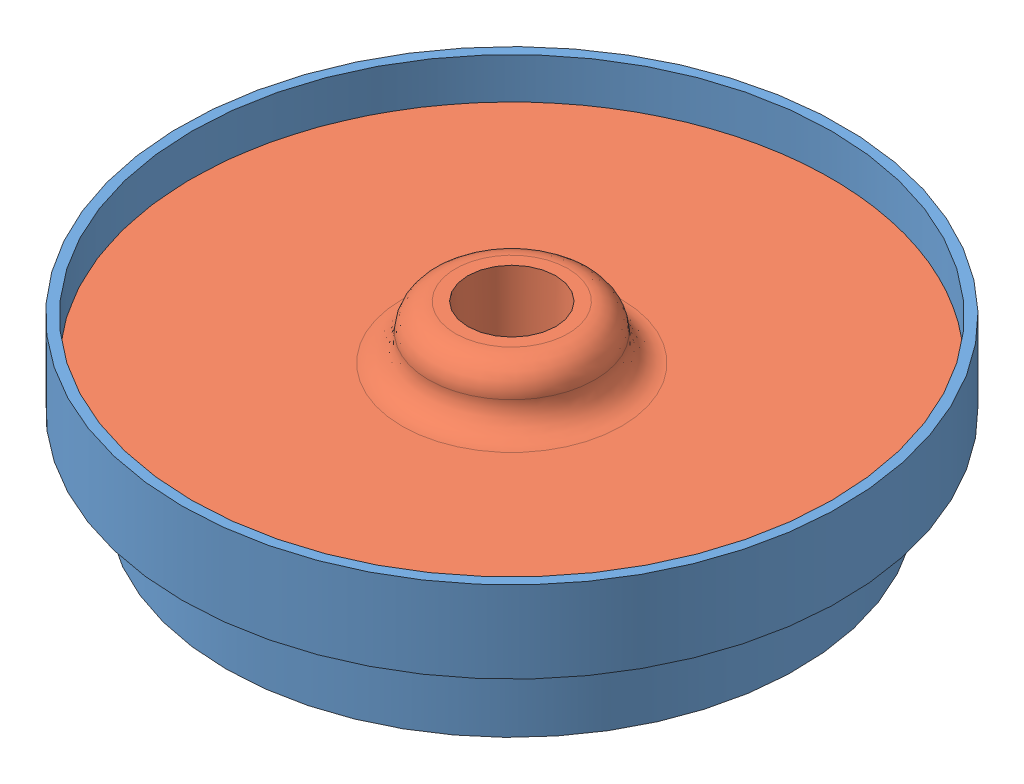
SolidWorks assembly Assem1, configuration Default. Lengths in mm.
Overall size (102.62 27.37 102.62).
2 component instances, 2 part files, 3 mates.
Components (placement in the parent):
- Main Ring Simplified-1: Main Ring Simplified [Default] at (0 51.3002 0) size (102.62 25.4 102.62)
- End Cap Simplified-1: End Cap Simplified [Default] at (0 52.8877 0) size (99.57 27.37 99.57)
Mates (geometry in assembly coordinates):
- Coincident3: coincident aligned: line of Main Ring Simplified-1 through (110 0 106.3002) axis (0 0 -1); line of assembly
- Coincident4: coincident aligned: line of End Cap Simplified-1 through (110 0 107.8877) axis (0 0 -1); line of assembly
- Coincident5: coincident anti-aligned: plane of Main Ring Simplified-1 through (-39.6875 52.8877 0) normal (0 1 0); plane of End Cap Simplified-1 through (-49.784 52.8877 0) normal (0 -1 0)
